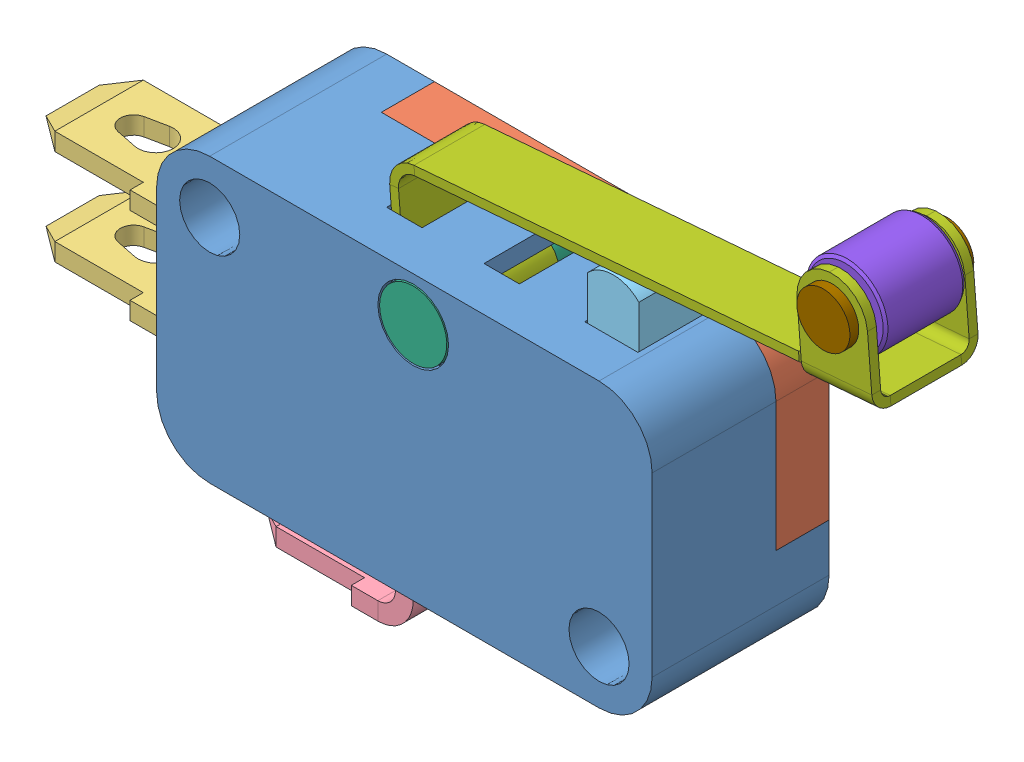
SolidWorks assembly Assembly - V-156-1C25 micro switch, configuration Idle. Lengths in mm.
Overall size (48.75 30.4 10).
10 component instances, 9 part files, 25 mates.
Components (placement in the parent):
- Body-1: Body [Domyślna] at origin size (28 16 10)
- Cover-1: Cover [Domyślna] at (0 0 3) x (-1 0 0) z (0 0 -1) size (28 16 3)
- Connector - straight-1: Connector - straight [Domyślna] at (-13 2.1 4.75) x (-1 0 0) z (0 -1 0) size (11 6.5 1)
- Connector - straight-2: Connector - straight [Domyślna] at (-13 -4.3 4.75) x (-1 0 0) z (0 1 0) size (11 6.5 1)
- Connector - bent-1: Connector - bent [Domyślna] at (-0.5 -11 4.75) x (-1 0 0) z (0 -1 0) size (10 6.5 5)
- Switch-2: Switch [Domyślna] at (9.2 8.4387 3.1) size (3.9 4.5 4.3)
- Rivet - long-1: Rivet - long [Domyślna] at (0.5 5.5 10) x (0 0 -1) z (0.574772 -0.818314 0) size (10 4 4)
- Arm-2: Arm [Domyślna] at (0 0 5) x (-1 0 0) z (0 0 -1) size (28.33 14.28 6)
- Roll-1: Roll [Domyślna] at (22.4283 16.0971 3) size (4.6 4.6 4.5)
- Rivet - short-1: Rivet - short [Domyślna] at (22.4283 16.0971 8.75) x (0 0 -1) z (1 0 0) size (7 3 3)
Mates (geometry in assembly coordinates):
- Koncentryczne1: concentric: cylinder of Body-1 through (-11 5 9) axis (0 0 -1) radius 2.7; cylinder of Cover-1 through (-11 5 0) axis (0 0 1) radius 2.7
- Koncentryczne2: concentric: cylinder of Body-1 through (11 -5 9) axis (0 0 -1) radius 2.7; cylinder of Cover-1 through (11 -5 0) axis (0 0 1) radius 2.7
- Wspólnie1: coincident: plane of Body-1 through (11 5 3) normal (0 0 -1); plane of Cover-1 through (11 5 3) normal (0 0 1)
- Wspólnie2: coincident: plane of Body-1 through (14.001 2.1 3) normal (0 -1 0); plane of Connector - straight-1 through (-13 2.1 4.75) normal (0 1 0)
- Wspólnie3: coincident: plane of Body-1 through (-13 1.3 9) normal (1 0 0); plane of Connector - straight-1 through (-13 1.1 8) normal (1 0 0)
- Wspólnie4: coincident: plane of Cover-1 through (14.001 2.1 1.5) normal (0 0 1); plane of Connector - straight-1 through (-13 1.1 1.5) normal (0 0 -1)
- Wspólnie5: coincident: plane of Body-1 through (14.001 -3.3 3) normal (0 -1 0); plane of Connector - straight-2 through (-13 -3.3 4.75) normal (0 1 0)
- Wspólnie6: coincident: plane of Body-1 through (-13 1.3 9) normal (1 0 0); plane of Connector - straight-2 through (-13 -3.3 1.5) normal (1 0 0)
- Wspólnie7: coincident: plane of Cover-1 through (14.001 -3.3 1.5) normal (0 0 1); plane of Connector - straight-2 through (-13 -3.3 1.5) normal (0 0 -1)
- Wspólnie8: coincident: plane of Body-1 through (-11 -7 9) normal (0 1 0); plane of Connector - bent-1 through (-2.5 -7 8) normal (0 1 0)
- Wspólnie9: coincident: plane of Cover-1 through (-1.5 8.001 1.5) normal (0 0 1); plane of Connector - bent-1 through (-2.5 -7 1.5) normal (0 0 -1)
- Wspólnie10: coincident: plane of Body-1 through (-1.5 8.001 3) normal (-1 0 0); plane of Connector - bent-1 through (-1.5 -7 8) normal (1 0 0)
- Symetrycznie1: symmetric: plane of Body-1 through (7.7 -8.001 7.5) normal (0 0 -1); plane of Cover-1 through (11 5 3) normal (0 0 1); plane of Switch-2 through (9.2 8.4387 5.25) normal (0 0 1)
- Wspólnie11: coincident: plane of Body-1 through (11 7 9) normal (0 -1 0); plane of Switch-2 through (7.75 7 7.4) normal (0 1 0)
- Symetrycznie2: symmetric: plane of Body-1 through (10.7 -8.001 3) normal (-1 0 0); plane of Body-1 through (7.7 -8.001 3) normal (1 0 0); plane of Switch-2 through (9.2 8.4387 3.1) normal (1 0 0)
- Koncentryczne3: concentric: cylinder of Body-1 through (0.5 5.5 -0.001) axis (0 0 1) radius 1; cylinder of Rivet - long-1 through (0.5 5.5 0.5) axis (0 0 1) radius 1
- Wspólnie12: coincident: plane of Cover-1 through (0.5 5.5 0.5) normal (0 0 -1); plane of Rivet - long-1 through (1.3183 6.0748 0.5) normal (0 0 1)
- Koncentryczne4: concentric: cylinder of Rivet - long-1 through (0.5 5.5 0.5) axis (0 0 1) radius 1; cylinder of Arm-2 through (0.5 5.5 7.25) axis (0 0 -1) radius 1.5
- Stycznie1: tangent: cylinder of Switch-2 through (9.2 9 7.4) axis (0 0 -1) radius 2; plane of Arm-2 through (24.7464 12.2726 7.25) normal (0.081165 -0.996701 0)
- Odległość1: distance = 0.25 mm: plane of Cover-1 through (11 5 3) normal (0 0 1); plane of Arm-2 through (-2.1645 10.0812 3.25) normal (0 0 -1)
- Koncentryczne5: concentric: cylinder of Arm-2 through (22.4283 16.0971 8.25) axis (0 0 -1) radius 1; cylinder of Roll-1 through (22.4283 16.0971 7.5) axis (0 0 -1) radius 1
- Symetrycznie3: symmetric: plane of Arm-2 through (0 0 2.25) normal (0 0 -1); plane of Arm-2 through (0 0 8.25) normal (0 0 1); plane of Roll-1 through (22.4283 16.0971 5.25) normal (0 0 1)
- Koncentryczne6: concentric: cylinder of Arm-2 through (22.4283 16.0971 8.25) axis (0 0 -1) radius 1; cylinder of Rivet - short-1 through (22.4283 16.0971 2.25) axis (0 0 1) radius 1
- Wspólnie17: coincident: plane of Arm-2 through (0 0 8.25) normal (0 0 1); plane of Rivet - short-1 through (22.4283 17.5971 8.25) normal (0 0 -1)
- Stycznie2: tangent: cylinder of Body-1 through (11 5 10) axis (0 0 -1) radius 3; plane of Arm-2 through (25.6655 4.8246 7.25) normal (-0.216237 -0.976341 0)
